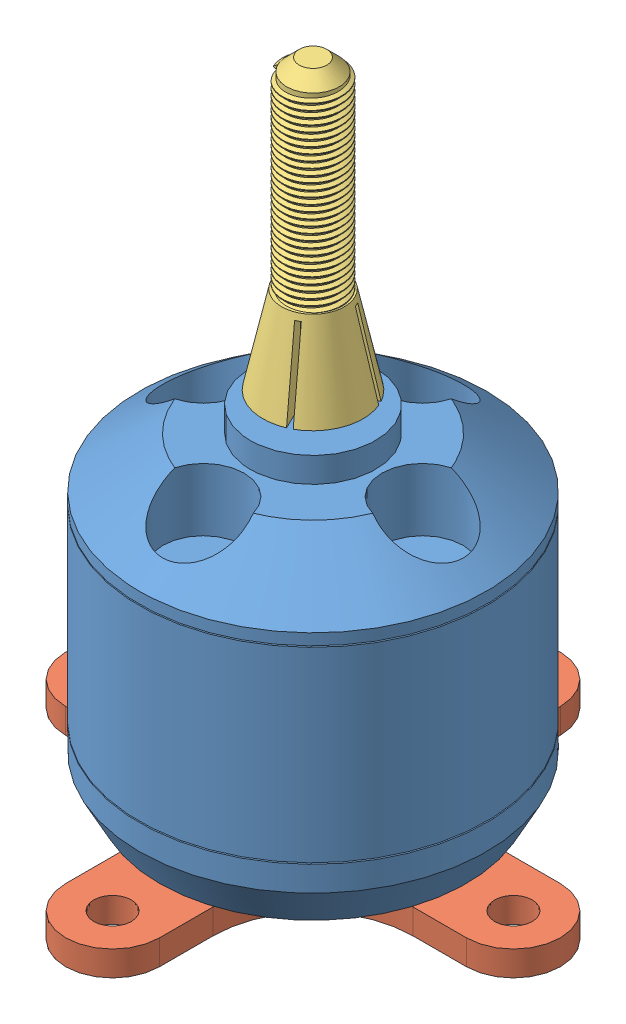
SolidWorks assembly Assem2, configuration Default. Lengths in mm.
Overall size (39.5 53 39.5).
3 component instances, 3 part files, 4 mates.
Components (placement in the parent):
- BR2212 Body-1: BR2212 Body [Default] at (1.5862 -0.2158 39.5728) size (27.7 40 27.7)
- BR2212 Mount-1: BR2212 Mount [Default] at (1.5862 -2.2158 39.5728) x (1 0 0) z (0 1 0) size (39.5 39.5 2)
- BR2212 Stock-1: BR2212 Stock [Default] at (1.5862 27.7842 39.5728) x (0.899356 0 -0.437218) z (0.437218 0 0.899356) size (7.99 23 7.99)
Mates (geometry in assembly coordinates):
- Concentric1: concentric: cylinder of BR2212 Body-1 through (1.5862 -1.8158 39.5728) axis (0 1 0) radius 1.585; circle of BR2212 Stock-1
- Distance1: distance = 1 mm: plane of BR2212 Stock-1 through (1.5862 27.7842 39.5728) normal (0 -1 0); plane of BR2212 Body-1 through (1.5862 26.7842 39.5728) normal (0 1 0)
- Coincident2: coincident: plane of BR2212 Body-1 through (1.5862 -0.2158 39.5728) normal (0 -1 0); plane of BR2212 Mount-1 through (-10.1638 -0.2158 27.8228) normal (0 1 0)
- Concentric2: concentric: cylinder of BR2212 Body-1 through (1.5862 -1.8158 39.5728) axis (0 1 0) radius 1.585; cylinder of BR2212 Mount-1 through (1.5862 -0.2158 39.5728) axis (0 -1 0) radius 5
